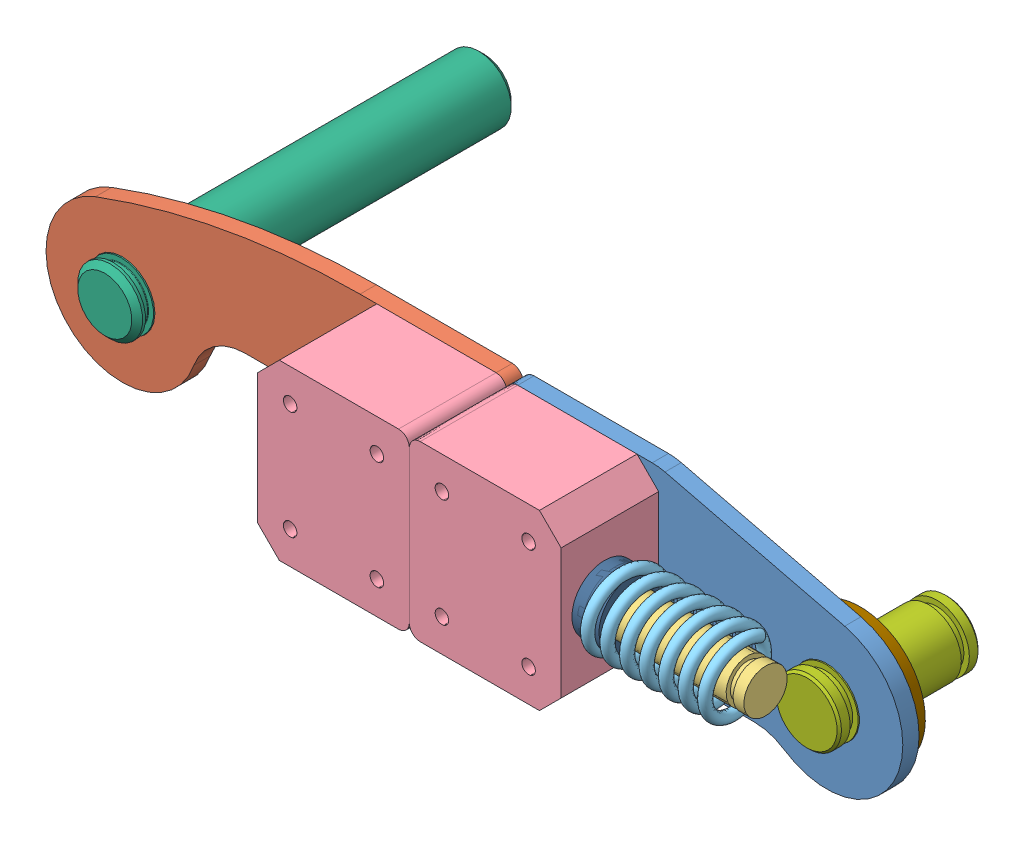
SolidWorks assembly Assem1-knee-mod1-hind-mirror, configuration Défaut. Lengths in mm.
Overall size (81.66 19.33 43.94).
16 component instances, 10 part files, 27 mates.
Components (placement in the parent):
- Part1-knee-mod3-hind-1: Part1-knee-mod3-hind [Défaut] at (3.122 0.7472 0) size (36.52 18.02 1.5)
- Part2-knee-mod3-hind-3: Part2-knee-mod3-hind [Défaut] at (-61.878 0.7472 0) x (-1 0 0) z (0 0 -1) size (42.52 18.02 1.5)
- part2-knee-mod1-1: part2-knee-mod1 [Default] at (-42.018 3.7472 5.75) x (0 0.983418 0.181353) z (0 0.181353 -0.983418) size (4 44.5 4)
- part4-knee-mod1-4: part4-knee-mod1 [Défaut] at (-19.378 3.7472 5.75) x (0 -1 0) z (1 0 0) size (16 9 14)
- Spring_DF-1670-2: Spring_DF-1670 [Défaut] at (-10.378 3.7472 5.75) x (0 0.936962 0.349431) z (1 0 0) size (8.62 8.62 12.7)
- d5l35-1: d5l35 [Default] at (-61.878 0.7472 -32.65) x (1 0 0) z (0 -1 0) size (6 35 6)
- al_d6_1-2: al_d6_1 [Default] at (3.122 0.7472 -10.41) x (1 0 0) z (0 -1 0) size (6 13 6)
- part4-knee-mod1-7: part4-knee-mod1 [Défaut] at (-33.378 3.7472 5.75) x (0 1 0) z (-1 0 0) size (16 9 14)
- lock washer for shafts_din-1: lock washer for shafts_din [PreviewCfg] at (-40.378 3.7472 5.75) x (0 0.99885 0.047948) z (1 0 0) size (2.25 1.94 0.2)
- lock washer for shafts_din-2: lock washer for shafts_din [PreviewCfg] at (0.842 3.7472 5.75) x (0 -1 0) z (-1 0 0) size (2.25 1.94 0.2)
- Washer-d6p5-12-1: Washer-d6p5-12 [Défaut] at (3.122 0.7472 -1.55) x (0.55859 0.829444 0) z (0 0 1) size (12 12 1.6)
- Washer-d6p5-12-2: Washer-d6p5-12 [Défaut] at (-61.878 0.7472 -1.55) x (0.55859 0.829444 0) z (0 0 1) size (12 12 1.6)
- washer-m3-6-3-1-1: washer-m3-6-3-1 [Default] at (-12.378 3.7472 5.75) size (1 6 6)
- washer-m3-6-3-1-2: washer-m3-6-3-1 [Default] at (-11.878 3.7472 5.75) size (1 6 6)
- washer-m3-6-3-1-3: washer-m3-6-3-1 [Default] at (-11.378 3.7472 5.75) size (1 6 6)
- washer-m3-6-3-1-4: washer-m3-6-3-1 [Default] at (-10.878 3.7472 5.75) size (1 6 6)
Mates (geometry in assembly coordinates):
- Distance1: distance = 0 mm anti-aligned: plane of Part1-knee-mod3-hind-1 through (-26.378 11.7472 0.75) normal (-1 0 0); plane of Part2-knee-mod3-hind-3 through (-26.378 11.7472 -0.75) normal (1 0 0)
- Coïncidente2: coincident aligned: plane of Part1-knee-mod3-hind-1 through (3.122 0.7472 0.75) normal (0 0 1); plane of Part2-knee-mod3-hind-3 through (-64.878 0.7472 0.75) normal (0 0 1)
- Coaxiale19: concentric anti-aligned: cylinder of part2-knee-mod1-1 through (-45.018 3.7472 5.75) axis (-1 0 0) radius 2; line of Spring_DF-1670-2 through (-10.378 3.7472 5.75) axis (1 0 0)
- Coaxiale20: concentric anti-aligned: cylinder of Part2-knee-mod3-hind-3 through (-64.878 0.7472 -0.75) axis (0 0 1) radius 3.025; cylinder of d5l35-1 through (-64.878 0.7472 -32.65) axis (0 0 -1) radius 3
- Coaxiale21: concentric aligned: cylinder of Part1-knee-mod3-hind-1 through (3.122 0.7472 0.75) axis (0 0 -1) radius 3.025; cylinder of al_d6_1-2 through (3.122 0.7472 -10.41) axis (0 0 -1) radius 3
- Distance6: distance = 0.1 mm aligned: plane of d5l35-1 through (-61.878 4.3472 0.85) normal (0 0 1); plane of Part2-knee-mod3-hind-3 through (-61.878 0.7472 0.75) normal (0 0 1)
- Coïncidente21: coincident aligned: plane of d5l35-1 through (-64.878 4.3472 0.85) normal (0 0 1); plane of al_d6_1-2 through (3.122 3.2472 0.85) normal (0 0 1)
- Coïncidente22: coincident anti-aligned: plane of Part1-knee-mod3-hind-1 through (3.122 0.7472 0.75) normal (0 0 1); plane of part4-knee-mod1-4 through (-12.378 11.7472 0.75) normal (0 0 -1)
- Coaxiale22: concentric aligned: cylinder of Part1-knee-mod3-hind-1 through (-15.378 8.7472 0.75) axis (0 0 -1) radius 0.85; cylinder of part4-knee-mod1-4 through (-15.378 8.7472 0.75) axis (0 0 -1) radius 0.625
- Coaxiale23: concentric aligned: cylinder of Part1-knee-mod3-hind-1 through (-15.378 -1.2528 0.75) axis (0 0 -1) radius 0.85; cylinder of part4-knee-mod1-4 through (-15.378 -1.2528 0.75) axis (0 0 -1) radius 0.625
- Coïncidente26: coincident anti-aligned: plane of Part2-knee-mod3-hind-3 through (-64.878 0.7472 0.75) normal (0 0 1); plane of part4-knee-mod1-7 through (-43.378 -4.2528 0.75) normal (0 0 -1)
- Coaxiale28: concentric anti-aligned: cylinder of Part2-knee-mod3-hind-3 through (-40.378 -1.2528 -0.75) axis (0 0 1) radius 0.85; cylinder of part4-knee-mod1-7 through (-40.378 -1.2528 0.75) axis (0 0 -1) radius 0.625
- Coaxiale29: concentric anti-aligned: cylinder of Part2-knee-mod3-hind-3 through (-40.378 8.7472 -0.75) axis (0 0 1) radius 0.85; cylinder of part4-knee-mod1-7 through (-40.378 8.7472 0.75) axis (0 0 -1) radius 0.625
- Distance7: distance = 2 mm aligned: plane of Spring_DF-1670-2 through (-10.378 3.7472 5.75) normal (1 0 0); plane of part4-knee-mod1-4 through (-12.378 11.7472 9.75) normal (1 0 0)
- Coïncidente29: coincident anti-aligned: plane of part2-knee-mod1-1 through (-43.378 5.3207 6.0402) normal (-1 0 0); plane of ? through (-43.378 3.7472 5.75) normal (1 0 0)
- Coaxiale31: concentric aligned: cylinder of part2-knee-mod1-1 through (-0.518 3.7472 5.75) axis (1 0 0) radius 1.6; cylinder of ? through (-43.578 3.7472 5.75) axis (1 0 0) radius 0.4
- Coaxiale34: concentric anti-aligned: cylinder of part2-knee-mod1-1 through (-45.018 3.7472 5.75) axis (-1 0 0) radius 2; cylinder of part4-knee-mod1-7 through (-43.378 3.7472 5.75) axis (1 0 0) radius 2
- Coaxiale35: concentric anti-aligned: cylinder of part2-knee-mod1-1 through (-0.518 3.7472 5.75) axis (1 0 0) radius 1.6; cylinder of ? through (-1.958 3.7472 5.75) axis (-1 0 0) radius 0.4
- Coïncidente30: coincident anti-aligned: plane of part2-knee-mod1-1 through (-2.158 5.886 6.1444) normal (1 0 0); plane of ? through (-2.158 3.7472 5.75) normal (-1 0 0)
- Coïncidente33: coincident aligned: plane of Part1-knee-mod3-hind-1 through (-26.378 11.7472 0.75) normal (0 1 0); plane of Part2-knee-mod3-hind-3 through (-29.378 11.7472 -0.75) normal (0 1 0)
- Coïncidente36: coincident anti-aligned: plane of part4-knee-mod1-7 through (-43.378 -4.2528 9.75) normal (-1 0 0); plane of ? through (-43.378 3.7472 5.75) normal (1 0 0)
- Concentric1: concentric aligned: cylinder of al_d6_1-2 through (3.122 0.7472 -10.41) axis (0 0 -1) radius 3; cylinder of Washer-d6p5-12-1 through (3.122 0.7472 -0.75) axis (0 0 -1) radius 3.25
- Coincident1: coincident anti-aligned: plane of Part1-knee-mod3-hind-1 through (3.122 0.7472 -0.75) normal (0 0 -1); plane of Washer-d6p5-12-1 through (3.122 0.7472 -0.75) normal (0 0 1)
- Coincident2: coincident anti-aligned: plane of Part2-knee-mod3-hind-3 through (-64.878 0.7472 -0.75) normal (0 0 -1); plane of Washer-d6p5-12-2 through (-64.878 0.7472 -0.75) normal (0 0 1)
- Concentric2: concentric aligned: cylinder of d5l35-1 through (-64.878 0.7472 -32.65) axis (0 0 -1) radius 3; cylinder of Washer-d6p5-12-2 through (-64.878 0.7472 -0.75) axis (0 0 -1) radius 3.25
- Coïncidente37: coincident anti-aligned: plane of part4-knee-mod1-4 through (-12.378 11.7472 9.75) normal (1 0 0); plane of washer-m3-6-3-1-1 through (-12.378 6.7472 5.75) normal (-1 0 0)
- Coaxiale36: concentric aligned: cylinder of part2-knee-mod1-1 through (-45.018 3.7472 5.75) axis (-1 0 0) radius 2; cylinder of washer-m3-6-3-1-1 through (-12.378 3.7472 5.75) axis (-1 0 0) radius 1.5
